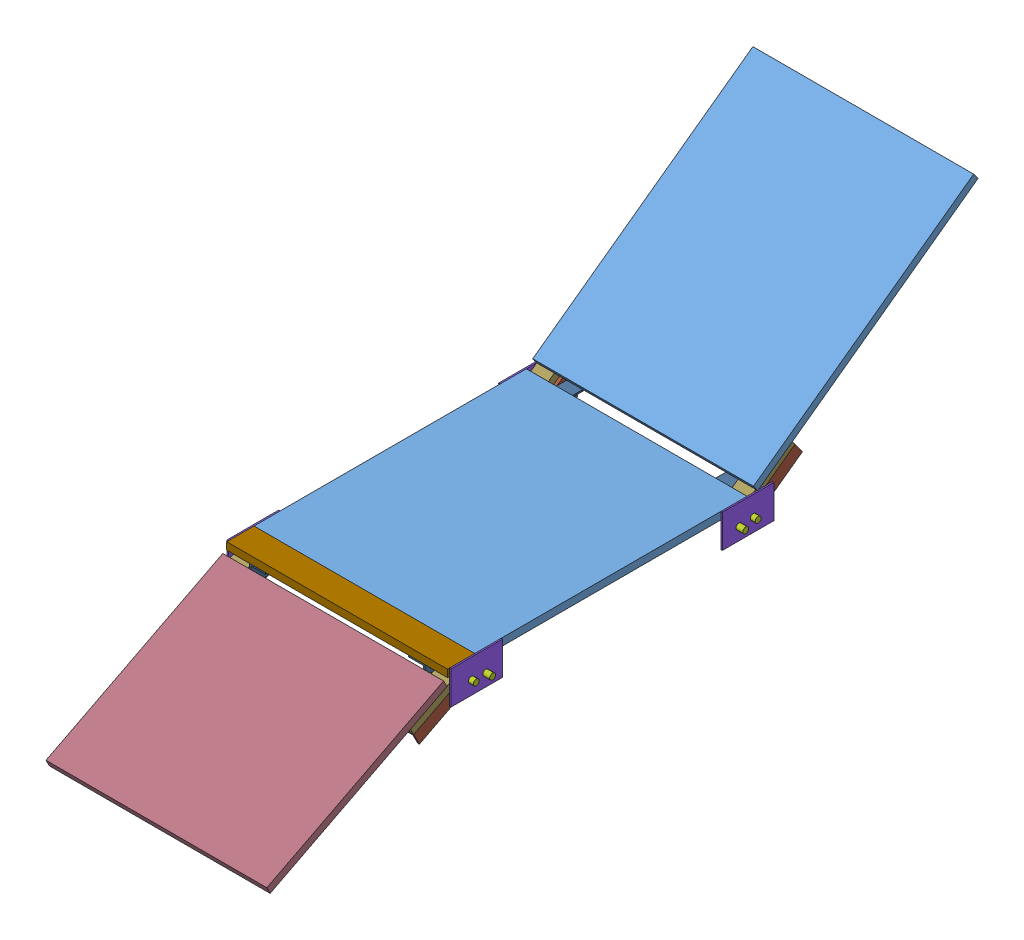
SolidWorks assembly 上半部, configuration 默认. Lengths in mm.
Overall size (322.41 371.23 963.55).
49 component instances, 13 part files, 32 mates.
Components (placement in the parent):
- pipi-1: pipi [默认] at (138.2489 214.7433 741.8932) x (1 0 0) z (0 -1 0) size (300 370 10)
- 零件1-2: 零件1 [默认] at (229.0232 204.7433 745.2266) x (0 0 -1) z (-1 0 0) size (46 34 32)
- 双输出涡轮蜗杆电机-1: 双输出涡轮蜗杆电机 [默认] at (222.7672 202.7433 755.0799) x (0 0 -1) z (0 -1 0) size (76.8 52.5 32)
- 联轴器-1: 联轴器 [默认] at (256.5232 186.7433 762.4328) x (0 -0.225386 -0.97427) z (1 0 0) size (14 14 20)
- M8光轴连接齿轮-1: M8光轴连接齿轮 [默认] at (268.5232 171.2912 762.2942) x (0 0.189293 -0.981921) z (1 0 0) size (8 8 100)
- 零件1-3: 零件1 [默认] at (250.5232 204.7433 759.6391) x (0 0 1) z (1 0 0) size (46 34 32)
- M8光轴连接齿轮-2: M8光轴连接齿轮 [默认] at (111.0232 171.2912 762.2942) x (0 0.189293 -0.981921) z (1 0 0) size (8 8 100)
- 联轴器-2: 联轴器 [默认] at (223.0232 186.7433 762.4328) x (0 0.225386 0.97427) z (-1 0 0) size (14 14 20)
- M8光轴连接齿轮-3: M8光轴连接齿轮 [默认] at (368.5232 171.2912 418.5715) x (0 0.189293 0.981921) z (-1 0 0) size (8 8 100)
- 联轴器-3: 联轴器 [默认] at (256.5232 186.7433 418.4328) x (0 0.225386 -0.97427) z (1 0 0) size (14 14 20)
- M8光轴连接齿轮-4: M8光轴连接齿轮 [默认] at (211.0232 171.2912 418.5715) x (0 0.189293 0.981921) z (-1 0 0) size (8 8 100)
- 联轴器-4: 联轴器 [默认] at (223.0232 186.7433 418.4328) x (0 -0.225386 0.97427) z (-1 0 0) size (14 14 20)
- 零件1-4: 零件1 [默认] at (229.0232 204.7433 421.2266) x (0 0 -1) z (-1 0 0) size (46 34 32)
- 双输出涡轮蜗杆电机-2: 双输出涡轮蜗杆电机 [默认] at (222.7672 170.7433 425.7857) x (0 0 1) z (0 1 0) size (76.8 52.5 32)
- 零件1-5: 零件1 [默认] at (250.5232 204.7433 435.6391) x (0 0 1) z (1 0 0) size (46 34 32)
- spur gear_gb-1: spur gear_gb [GB - Spur gear 1M 20T 20PA 12FW ---S20B75H20L8.0N] at (364.9794 186.7433 762.4328) size (20 21.8 21.8)
- 零件3-1: 零件3 [默认] at (78.5671 164.7773 729.4471) x (0 0 -1) z (1 0 0) size (8 8 24)
- 零件2-1: 零件2 [默认] at (87.8028 179.7301 742.6787) x (0 0 -1) z (1 0 0) size (70 45 2)
- 零件3-2: 零件3 [默认] at (376.9794 164.7773 729.4471) x (0 0 -1) z (1 0 0) size (8 8 24)
- 零件2-2: 零件2 [默认] at (389.7437 179.7301 742.6787) x (0 0 -1) z (1 0 0) size (70 45 2)
- spur gear_gb-5: spur gear_gb [GB - Spur gear 1M 20T 20PA 12FW ---S20B75H20L8.0N] at (102.0491 188.2033 781.9328) x (1 0 0) z (0 0.077189 0.997016) size (20 21.8 21.8)
- 零件3-3: 零件3 [默认] at (81.2594 164.6271 750.0781) x (0 -0.049638 -0.998767) z (1 0 0) size (8 8 24)
- 零件3-4: 零件3 [默认] at (125.8375 166.2373 814.9185) x (0 0 1) z (-1 0 0) size (8 8 24)
- 零件4-1: 零件4 [默认] at (132.1319 204.7433 785.4585) x (-1 0 0) z (0 1 0) size (300 37 10)
- 零件5-1: 零件5 [默认] at (69.1841 204.7433 721.8718) x (0 0 -1) z (0 -1 0) size (37 22 25)
- 零件6-1: 零件6 [默认] at (93.3062 185.4021 787.0184) x (0 -0.456387 0.889781) z (-1 0 0) size (87 17 28)
- 零件6-2: 零件6 [默认] at (362.2994 185.4021 787.0184) x (0 -0.456387 0.889781) z (-1 0 0) size (87 17 28)
- 零件5-2: 零件5 [默认] at (410.4215 204.7433 865.9939) x (0 0 1) z (0 -1 0) size (37 22 25)
- 零件3-5: 零件3 [默认] at (377.768 166.2373 814.9185) x (0 0 1) z (-1 0 0) size (8 8 24)
- 零件7-1: 零件7 [默认] at (115.3062 176.5586 823.2601) x (0 0.456387 -0.889781) z (0 0.889781 0.456387) size (70 24 10)
- 零件7-2: 零件7 [默认] at (364.2994 173.8995 828.4444) x (0 -0.456387 0.889781) z (0 0.889781 0.456387) size (70 24 10)
- 零件2-3: 零件2 [默认] at (391.7437 179.7301 438.187) x (0 0 1) z (-1 0 0) size (70 45 2)
- 零件5-3: 零件5 [默认] at (410.4215 204.7433 458.9939) x (0 0 1) z (0 -1 0) size (37 22 25)
- 零件3-6: 零件3 [默认] at (353.768 166.2373 365.9471) x (0 0 -1) z (1 0 0) size (8 8 24)
- 零件3-7: 零件3 [默认] at (101.8375 166.2373 365.9471) x (0 0 -1) z (1 0 0) size (8 8 24)
- 零件3-8: 零件3 [默认] at (105.2594 164.6271 430.7875) x (0 -0.049638 0.998767) z (-1 0 0) size (8 8 24)
- 零件5-4: 零件5 [默认] at (69.1841 204.7433 314.8718) x (0 0 -1) z (0 -1 0) size (37 22 25)
- 零件2-4: 零件2 [默认] at (89.8028 179.7301 438.187) x (0 0 1) z (-1 0 0) size (70 45 2)
- 零件3-9: 零件3 [默认] at (374.3461 164.6271 750.0781) x (0 -0.049638 -0.998767) z (1 0 0) size (8 8 24)
- 零件3-10: 零件3 [默认] at (105.2594 164.6271 430.7875) x (0 -0.049638 0.998767) z (-1 0 0) size (8 8 24)
- 零件3-11: 零件3 [默认] at (398.3461 164.6271 430.7875) x (0 -0.049638 0.998767) z (-1 0 0) size (8 8 24)
- 零件6-3: 零件6 [默认] at (116.9388 191.4795 394.1394) x (0 0.588412 -0.808561) z (1 0 0) size (87 17 28)
- 零件7-3: 零件7 [默认] at (114.9388 227.9261 375.7887) x (0 -0.588412 0.808561) z (0 -0.808561 -0.588412) size (70 24 10)
- 零件6-4: 零件6 [默认] at (386.6668 191.4795 394.1394) x (0 0.588412 -0.808561) z (1 0 0) size (87 17 28)
- 零件7-4: 零件7 [默认] at (364.6668 219.8405 369.9046) x (0 -0.588412 0.808561) z (0 0.808561 0.588412) size (70 24 10)
- pipi-3: pipi [默认] at (139.8176 413.6722 120.3866) x (1 0 0) z (0 0.808561 0.588412) size (300 370 10)
- 零件3-12: 零件3 [默认] at (102.5671 164.7773 451.4185) x (0 0 1) z (-1 0 0) size (8 8 24)
- 零件3-13: 零件3 [默认] at (400.9794 164.7773 451.4185) x (0 0 1) z (-1 0 0) size (8 8 24)
- 零件8-1: 零件8 [默认] at (354.8866 173.3458 851.2777) x (0 0.889781 0.456387) z (0 0.456387 -0.889781) size (10 300 270)
Mates (geometry in assembly coordinates):
- 同心29: concentric anti-aligned: circle of 零件1-2; circle of 双输出涡轮蜗杆电机-1
- 重合73: coincident anti-aligned: plane of 零件1-2 through (229.0232 204.7433 745.2266) normal (1 0 0); plane of 双输出涡轮蜗杆电机-1 through (229.0232 170.7433 775.4328) normal (-1 0 0)
- 平行3: parallel aligned: plane of 零件1-2 through (227.0232 204.7433 775.4328) normal (0 1 0); plane of 双输出涡轮蜗杆电机-1 through (222.7672 202.7433 755.0799) normal (0 1 0)
- 重合75: coincident anti-aligned: plane of pipi-1 through (138.2489 204.7433 741.8932) normal (0 -1 0); plane of 零件1-2 through (227.0232 204.7433 775.4328) normal (0 1 0)
- 重合76: coincident aligned: plane of pipi-1 through (89.8028 204.7433 775.4328) normal (0 0 1); plane of 双输出涡轮蜗杆电机-1 through (250.5232 170.7433 775.4328) normal (0 0 1)
- 同心30: concentric aligned: cylinder of 双输出涡轮蜗杆电机-1 through (266.5232 186.7433 762.4328) axis (-1 0 0) radius 3; cylinder of 联轴器-1 through (266.5232 186.7433 762.4328) axis (-1 0 0) radius 3
- 重合78: coincident anti-aligned: plane of 双输出涡轮蜗杆电机-1 through (266.5232 186.7433 762.4328) normal (1 0 0); plane of 联轴器-1 through (266.5232 186.7433 762.4328) normal (-1 0 0)
- 同心31: concentric anti-aligned: cylinder of 联轴器-1 through (268.5232 186.7433 762.4328) axis (1 0 0) radius 4; cylinder of M8光轴连接齿轮-1 through (368.5232 186.7433 762.4328) axis (-1 0 0) radius 4
- 重合79: coincident anti-aligned: plane of 联轴器-1 through (268.5232 186.7433 762.4328) normal (1 0 0); plane of M8光轴连接齿轮-1 through (268.5232 186.7433 762.4328) normal (-1 0 0)
- 同心321: concentric aligned: cylinder of M8光轴连接齿轮-1 through (368.5232 186.7433 762.4328) axis (-1 0 0) radius 4; cylinder of spur gear_gb-1 through (384.9794 186.7433 762.4328) axis (-1 0 0) radius 4
- 重合82: coincident aligned: plane of pipi-1 through (138.2489 214.7433 741.8932) normal (0 1 0); plane of 零件2-1 through (89.8028 214.7433 809.8461) normal (0 1 0)
- 重合84: coincident anti-aligned: plane of pipi-1 through (89.8028 204.7433 405.4328) normal (-1 0 0); plane of 零件2-1 through (89.8028 179.7301 742.6787) normal (1 0 0)
- 同心34: concentric aligned: cylinder of spur gear_gb-5 through (122.0492 188.2033 781.9328) axis (-1 0 0) radius 4; cylinder of 零件3-3 through (105.2594 188.2033 781.9328) axis (-1 0 0) radius 4
- 同心35: concentric anti-aligned: cylinder of spur gear_gb-5 through (122.0492 188.2033 781.9328) axis (-1 0 0) radius 4; cylinder of 零件3-4 through (101.8375 188.2033 781.9328) axis (1 0 0) radius 4
- 重合86: coincident aligned: plane of pipi-1 through (138.2489 214.7433 741.8932) normal (0 1 0); plane of 零件4-1 through (132.1319 214.7433 785.4585) normal (0 1 0)
- 重合87: coincident anti-aligned: plane of 零件2-2 through (389.7437 179.7301 742.6787) normal (-1 0 0); plane of 零件4-1 through (389.7437 214.7433 775.4328) normal (1 0 0)
- 重合88: coincident anti-aligned: plane of pipi-1 through (89.8028 204.7433 775.4328) normal (0 0 1); plane of 零件4-1 through (89.7437 214.7433 775.4328) normal (0 0 -1)
- 重合91: coincident anti-aligned: plane of 零件4-1 through (132.1319 204.7433 785.4585) normal (0 -1 0); plane of 零件5-1 through (69.1841 204.7433 721.8718) normal (0 1 0)
- 同心36: concentric anti-aligned: cylinder of 零件3-4 through (101.8375 188.2033 781.9328) axis (1 0 0) radius 4; cylinder of 零件6-1 through (119.3062 188.2033 781.9328) axis (-1 0 0) radius 4
- 同心38: concentric anti-aligned: cylinder of 零件3-4 through (101.8375 188.2033 781.9328) axis (1 0 0) radius 4; cylinder of 零件6-1 through (119.3062 188.2033 781.9328) axis (-1 0 0) radius 4
- 同心39: concentric anti-aligned: cylinder of 零件3-3 through (105.2594 188.2033 781.9328) axis (-1 0 0) radius 4; cylinder of 零件3-4 through (101.8375 188.2033 781.9328) axis (1 0 0) radius 4
- 同心41: concentric aligned: cylinder of 零件3-4 through (101.8375 188.2033 781.9328) axis (1 0 0) radius 4; cylinder of 零件5-1 through (94.5919 188.2033 781.9328) axis (1 0 0) radius 4
- 重合93: coincident aligned: plane of 零件4-1 through (389.7437 214.7433 812.4328) normal (0 0 1); plane of 零件5-1 through (120.5919 179.7433 812.4328) normal (0 0 1)
- 重合98: coincident anti-aligned: plane of 零件6-1 through (91.3062 195.0819 787.1468) normal (0 0.889781 0.456387); plane of 零件7-1 through (115.3062 176.5586 823.2601) normal (0 -0.889781 -0.456387)
- 重合99: coincident: plane of 零件6-1 through (91.3062 159.2555 856.9946) normal (0 -0.456387 0.889781); line of 零件7-1 through (91.3062 159.2555 856.9946) axis (1 0 0)
- 重合100: coincident aligned: plane of 零件6-1 through (91.3062 187.5188 783.2675) normal (-1 0 0); plane of 零件7-1 through (91.3062 168.1533 861.5585) normal (-1 0 0)
- 重合102: coincident anti-aligned: plane of 零件6-2 through (360.2994 195.0819 787.1468) normal (0 0.889781 0.456387); plane of 零件7-2 through (364.2994 173.8995 828.4444) normal (0 -0.889781 -0.456387)
- 重合103: coincident aligned: plane of 零件6-2 through (388.2994 187.5188 783.2675) normal (1 0 0); plane of 零件7-2 through (388.2994 200.1004 799.2738) normal (1 0 0)
- 重合104: coincident aligned: plane of 零件6-2 through (360.2994 159.2555 856.9946) normal (0 -0.456387 0.889781); plane of 零件7-2 through (388.2994 168.1533 861.5585) normal (0 -0.456387 0.889781)
- 重合111: coincident aligned: plane of 零件6-3 through (92.9388 200.9602 395.8487) normal (0 -0.588412 0.808561); plane of 零件7-3 through (90.9388 200.9602 395.8487) normal (0 -0.588412 0.808561)
- 重合112: coincident aligned: plane of 零件6-3 through (90.9388 189.086 397.72) normal (-1 0 0); plane of 零件7-3 through (90.9388 242.149 339.2494) normal (-1 0 0)
- 重合113: coincident anti-aligned: plane of 零件6-3 through (118.9388 195.9587 402.7215) normal (0 0.808561 0.588412); plane of 零件7-3 through (114.9388 219.8405 369.9046) normal (0 -0.808561 -0.588412)
